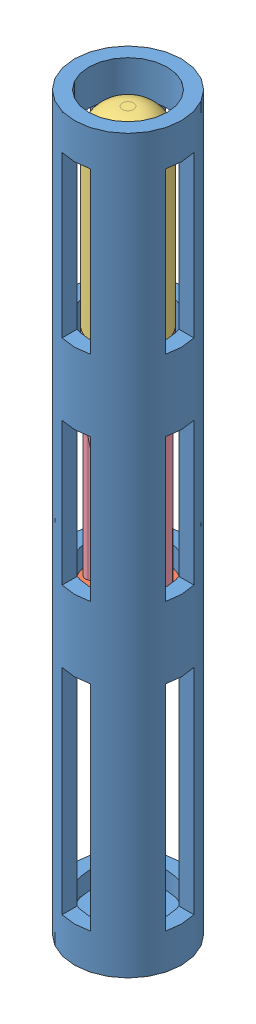
SolidWorks assembly Test, configuration Default. Lengths in mm.
Overall size (38.1 260.35 38.1).
5 component instances, 4 part files, 4 mates.
Components (placement in the parent):
- Tube-1: Tube [Default] at (29.1332 -5.2579 261.8445) size (38.1 260.35 38.1)
- Block-1: Block [Default] at (29.1332 102.6921 261.8445) x (1 0 0) z (0 0 -1) size (26.67 12.7 26.67)
- MS-A-0015-Flywheel Torpedo-1: MS-A-0015-Flywheel Torpedo [Default] at (15.7123 199.5521 232.2859) size (31.6 147.3 31.6)
  - MS-P-0052- Flywheel Torpedo Body-1: MS-P-0052- Flywheel Torpedo Body [Default] at (13.4209 3.732 29.5587) size (24 67.3 24)
  - MS-P-0051- Flywheel Torpedo Fins-1: MS-P-0051- Flywheel Torpedo Fins [Default] at (13.4209 -0.86 29.5587) x (-0.916326 0 0.400432) z (0.400432 0 0.916326) size (24 96 24)
Mates (geometry in assembly coordinates):
- Concentric3: concentric anti-aligned: circle of Tube-1; circle of Block-1
- Concentric4: concentric anti-aligned: circle of Block-1; circle of MS-A-0015-Flywheel Torpedo-1/MS-P-0052- Flywheel Torpedo Body-1
- Coincident3: coincident anti-aligned: plane of Block-1 through (29.1332 102.6921 261.8445) normal (0 1 0); plane of MS-A-0015-Flywheel Torpedo-1/MS-P-0051- Flywheel Torpedo Fins-1 through (29.1332 102.6921 261.8445) normal (0 -1 0)
- Concentric5: concentric anti-aligned: cylinder of Tube-1 through (29.1332 96.3421 242.7945) axis (0 0 1) radius 2.2479; cylinder of Block-1 through (29.1332 96.3421 275.1795) axis (0 0 -1) radius 2.2479
